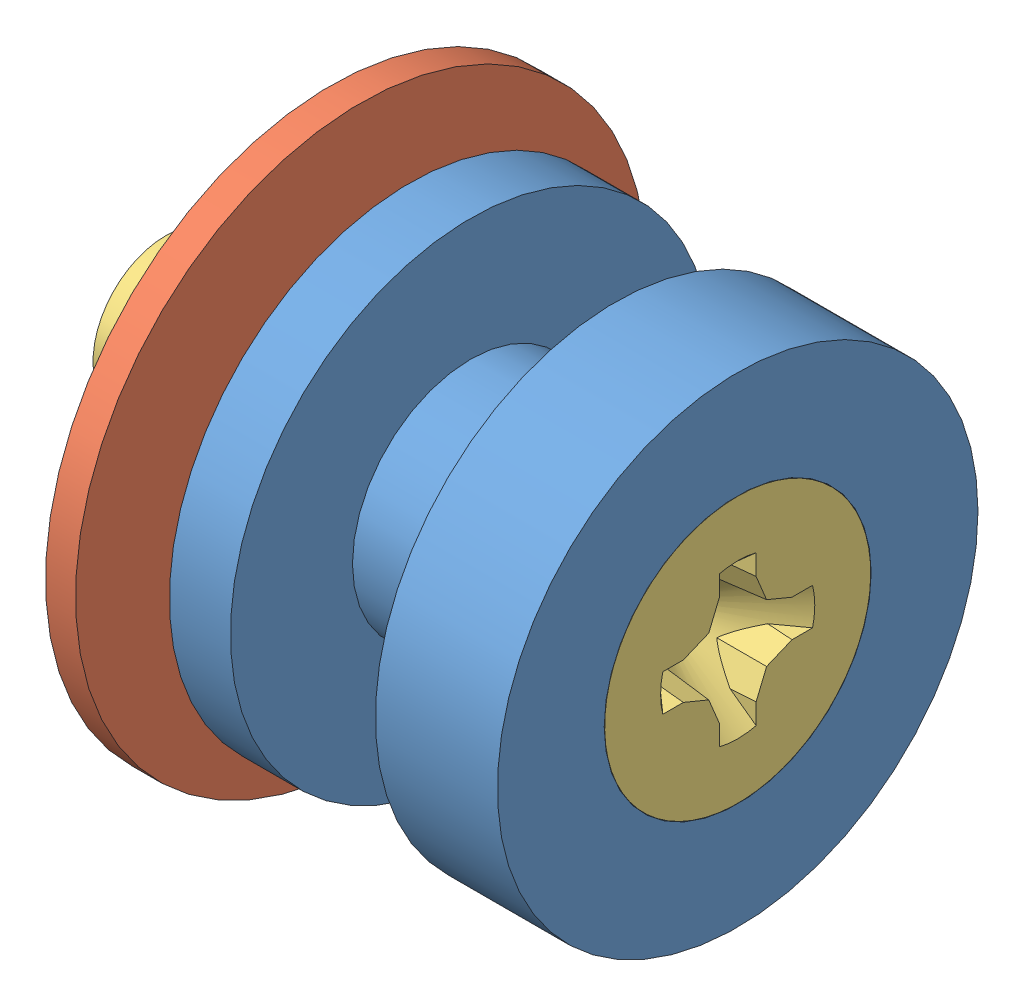
SolidWorks assembly S1B_Railguide, configuration Default. Lengths in mm.
Overall size (19.05 19 19).
3 component instances, 3 part files, 9 mates.
Components (placement in the parent):
- S1B_Railguide_Bolt-1: S1B_Railguide_Bolt [Default] at origin size (10.92 16 16)
- S1B_Welded_Nut_Railguide-1: S1B_Welded_Nut_Railguide [Default] at (-2.6264 0 0) x (0 0 1) z (-1 0 0) size (19 19 11)
- S1B_10-32_Flathead_RailguideScrew-2: S1B_10-32_Flathead_RailguideScrew [91099A365] at (1.397 0 0) x (-1 0 0) z (0 0 -1) size (19.05 8.95 8.95)
Mates (geometry in assembly coordinates):
- Coincident1: coincident aligned: plane of S1A_Railguide_Bolt-1 through (0 0 0) normal (0 0 1)
- Coincident2: coincident aligned: plane of S1A_Railguide_Bolt-1 through (0 0 0) normal (0 1 0)
- Coincident3: coincident aligned: plane of S1A_Railguide_Bolt-1 through (0 0 0) normal (1 0 0)
- Concentric1: concentric aligned: cylinder of S1A_Railguide_Bolt-1 through (0 0 0) axis (1 0 0) radius 3.429; cylinder of S1A_10-32_Flathead_RailguideScrew-2 through (10.922 0 0) axis (1 0 0) radius 2.413
- Coincident4: coincident aligned: plane of S1A_Railguide_Bolt-1 through (10.922 0 0) normal (1 0 0); plane of S1A_10-32_Flathead_RailguideScrew-2 through (10.922 0 0) normal (1 0 0)
- Concentric2: concentric anti-aligned: cylinder of S1A_Welded_Nut_Railguide-1 through (-0.0864 0 0) axis (-1 0 0) radius 2.5; cylinder of S1A_10-32_Flathead_RailguideScrew-2 through (10.922 0 0) axis (1 0 0) radius 2.413
- Parallel1: parallel aligned: plane of S1A_Welded_Nut_Railguide-1 through (-2.6264 0 0) normal (0 0 1)
- Distance1: distance = 1.6256 mm anti-aligned: plane of S1A_Welded_Nut_Railguide-1 through (-1.6256 0 0) normal (1 0 0); plane of S1A_Railguide_Bolt-1 through (0 0 0) normal (-1 0 0)
- Parallel2: parallel aligned: plane of S1A_10-32_Flathead_RailguideScrew-2 through (1.397 0 0) normal (0 1 0)
